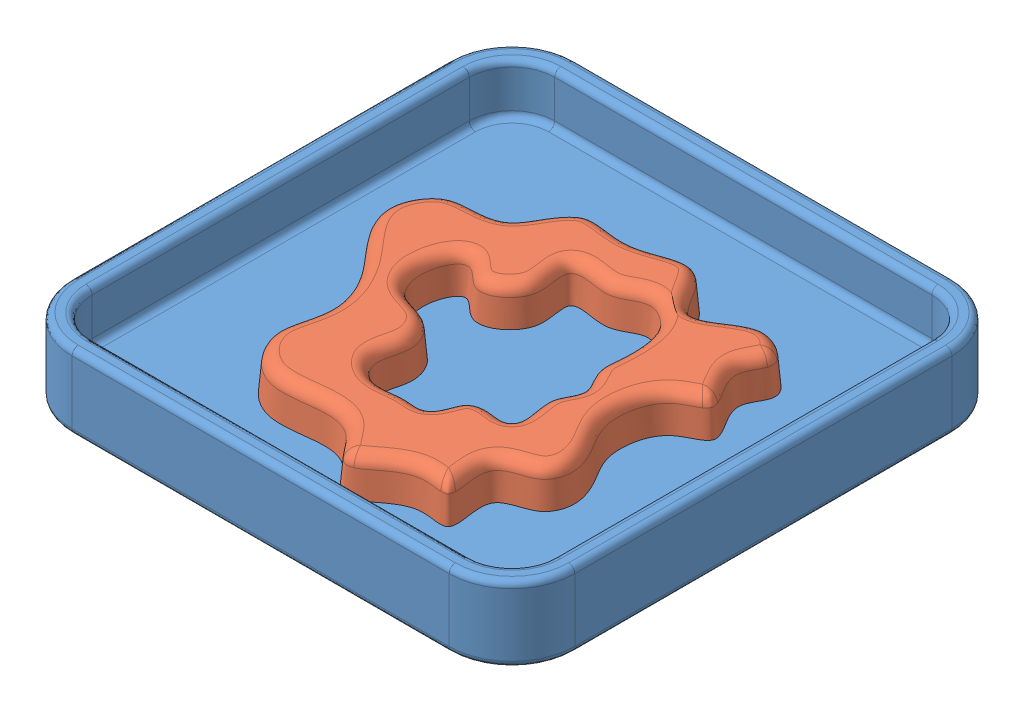
SolidWorks assembly Assem6, configuration Default. Lengths in mm.
Overall size (40 6 40).
2 component instances, 2 part files, 1 mates.
Components (placement in the parent):
- Tile-1: Tile [Default] at (10.2838 18.0065 33.0657) size (40 6 40)
- Distortion-1: Distortion [Default] at (10.1637 20.0065 33.1893) size (28.99 3.3 29.68)
Mates (geometry in assembly coordinates):
- Coincident1: coincident anti-aligned: plane of Tile-1 through (-4.7162 20.0065 48.0657) normal (0 1 0); plane of Distortion-1 through (13.7925 20.0065 21.6638) normal (0 -1 0)
